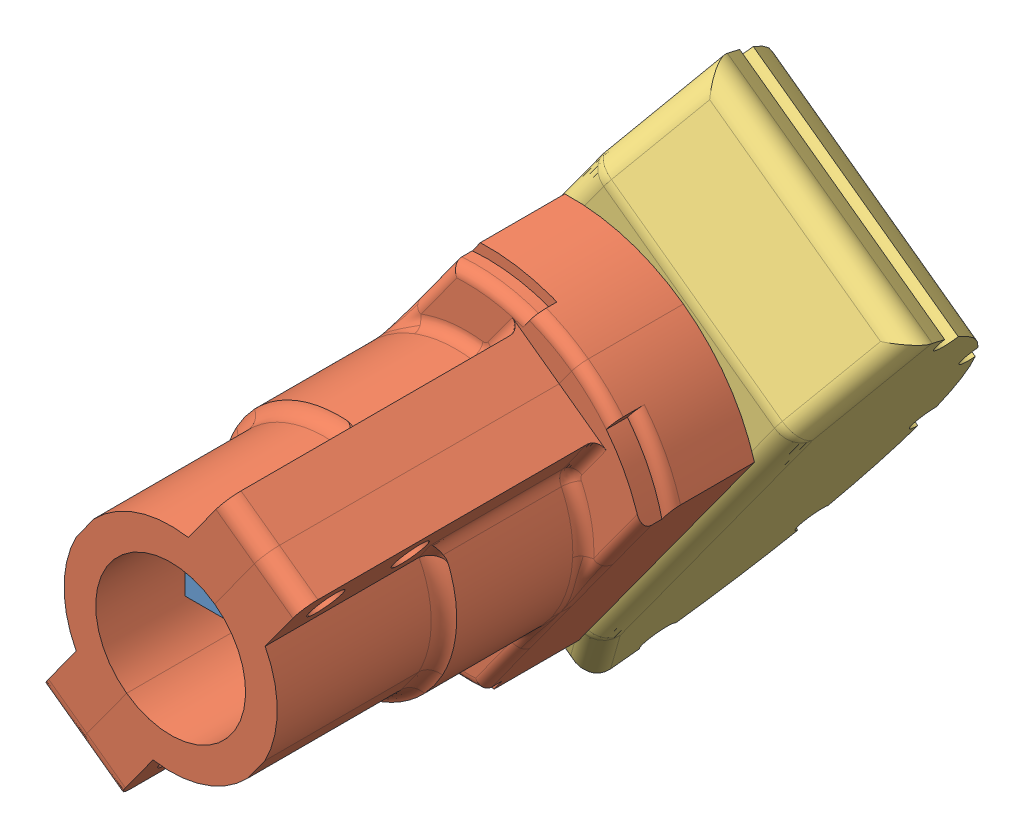
SolidWorks assembly contact_TPU_footpad, configuration Default. Lengths in mm.
Overall size (50.07 56.32 61.96).
4 component instances, 3 part files, 11 mates.
Components (placement in the parent):
- touch_sensor_bare-1: touch_sensor_bare [Default] at (20.4117 -8.338 -6.1063) size (20.12 21.47 40)
- contact_switch_mount_half_TPU_footpad-1: contact_switch_mount_half_TPU_footpad [Default] at (20.4117 -8.338 13.8937) x (0.587441 0.809267 0) z (0.809267 -0.587441 0) size (36 38.09 11.15)
- flat_foot_sticker-1: flat_foot_sticker [Default] at (20.4117 -8.338 -10.1063) x (0.587441 0.809267 0) z (-0.809267 0.587441 0) size (52.17 29.96 24)
- contact_switch_mount_half_TPU_footpad-2: contact_switch_mount_half_TPU_footpad [Default] at (20.4117 -8.338 13.8937) x (-0.587441 -0.809267 0) z (-0.809267 0.587441 0) size (36 38.09 11.15)
Mates (geometry in assembly coordinates):
- Concentric1: concentric anti-aligned: cylinder of touch_sensor_bare-1 through (20.4117 -8.338 5.8937) axis (0 0 -1) radius 8; cylinder of contact_switch_mount_half_TPU_footpad-1 through (20.4117 -8.338 -6.1063) axis (0 0 1) radius 8.1
- Coincident2: coincident anti-aligned: plane of touch_sensor_bare-1 through (20.4117 -8.338 -10.1063) normal (0 0 -1); plane of flat_foot_sticker-1 through (20.4117 -8.338 -10.1063) normal (0 0 1)
- Concentric2: concentric aligned: cylinder of touch_sensor_bare-1 through (20.4117 -8.338 -10.1063) axis (0 0 1) radius 6; cylinder of flat_foot_sticker-1 through (20.4117 -8.338 -27.1063) axis (0 0 1) radius 4
- Coincident3: coincident anti-aligned: plane of contact_switch_mount_half_TPU_footpad-1 through (7.719 -25.8236 -8.1063) normal (-0.809267 0.587441 0); plane of contact_switch_mount_half_TPU_footpad-2 through (33.1044 9.1477 -8.1063) normal (0.809267 -0.587441 0)
- Concentric3: concentric anti-aligned: cylinder of contact_switch_mount_half_TPU_footpad-1 through (4.3672 -11.5456 9.8937) axis (0.809267 -0.587441 0) radius 1.575; cylinder of contact_switch_mount_half_TPU_footpad-2 through (22.3329 -24.5868 9.8937) axis (-0.809267 0.587441 0) radius 1.575
- Concentric4: concentric anti-aligned: cylinder of contact_switch_mount_half_TPU_footpad-1 through (4.3672 -11.5456 17.8937) axis (0.809267 -0.587441 0) radius 1.575; cylinder of contact_switch_mount_half_TPU_footpad-2 through (22.3329 -24.5868 17.8937) axis (-0.809267 0.587441 0) radius 1.575
- Coincident4: coincident anti-aligned: plane of touch_sensor_bare-1 through (20.4117 -8.338 -10.1063) normal (0 0 -1); plane of flat_foot_sticker-1 through (20.4117 -8.338 -10.1063) normal (0 0 1)
- Parallel1: parallel aligned: plane of flat_foot_sticker-1 through (6.8913 -16.75 -13.1063) normal (-0.809267 0.587441 0); plane of contact_switch_mount_half_TPU_footpad-2 through (24.3015 15.9161 -16.1063) normal (-0.809267 0.587441 0)
- Coincident5: coincident anti-aligned: plane of flat_foot_sticker-1 through (20.4117 -8.338 -13.1063) normal (0 0 -1); plane of contact_switch_mount_half_TPU_footpad-2 through (29.2233 3.801 -13.1063) normal (0 0 1)
- Symmetric1: symmetric aligned: plane of assembly through (17.3317 -12.581 0) normal (0.809267 -0.587441 0); plane of contact_switch_mount_half_TPU_footpad-2 through (23.0928 6.4205 -44.4479) normal (0.809267 -0.587441 0); plane of contact_switch_mount_half_TPU_footpad-1 through (30.0585 -6.1133 -44.4479) normal (-0.809267 0.587441 0)
- Symmetric2: symmetric aligned: cylinder of contact_switch_mount_half_TPU_footpad-1 through (20.4117 -8.338 5.8937) axis (0 0 -1) radius 15; cylinder of contact_switch_mount_half_TPU_footpad-1 through (20.4117 -8.338 5.8937) axis (0 0 -1) radius 15
